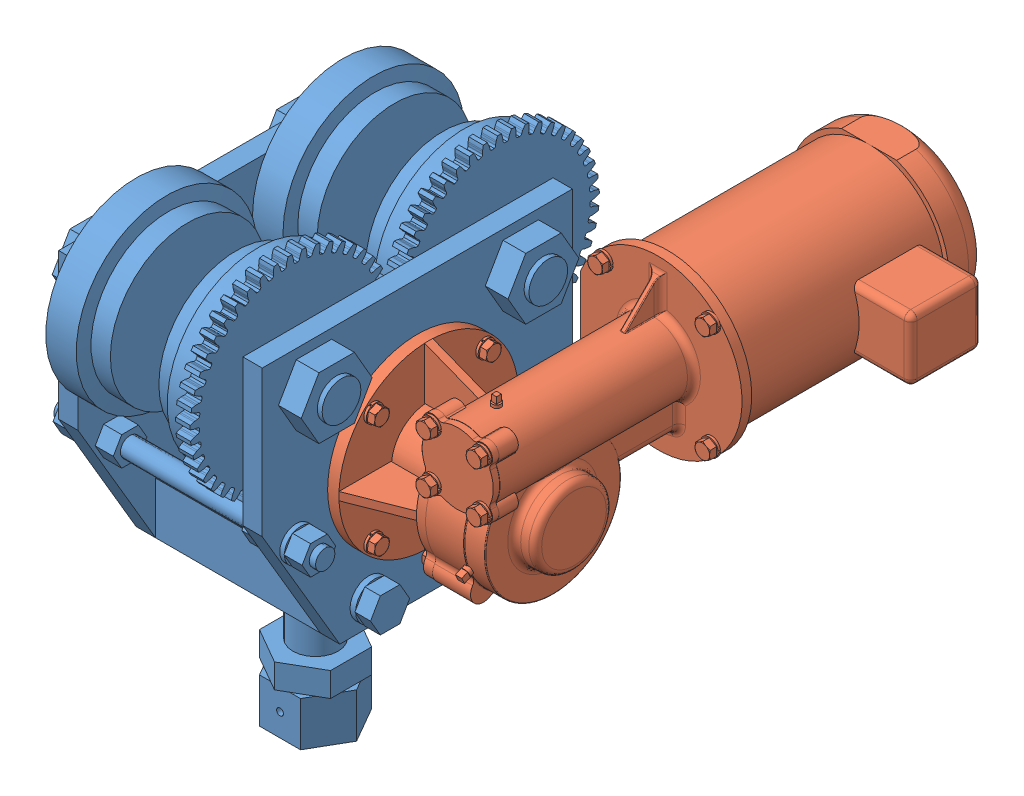
SolidWorks assembly M2630C-RH, configuration Default. Lengths in mm.
Overall size (465.77 492.84 570.37).
2 component instances, 2 part files, 3 mates.
Components (placement in the parent):
- Copy of M2630C-TROLLEY-SECTION^M2630C-RH-1: Copy of M2630C-TROLLEY-SECTION^M2630C-RH [3.25 PAT TRACK] at origin size (257.18 492.84 402.11) (virtual)
- Copy of SDT GEAR REDUCER RH M2630 TEMPLATE^M2630C-RH-1: Copy of SDT GEAR REDUCER RH M2630 TEMPLATE^M2630C-RH [Default] at (212.725 137.4775 0) size (238.76 237.33 457.42) (virtual)
Mates (geometry in assembly coordinates):
- Coincident1: coincident aligned: plane of Copy of M2630C-TROLLEY-SECTION^M2630C-RH-1 through (0 137.4775 0) normal (0 1 0); plane of Copy of SDT GEAR REDUCER RH M2630 TEMPLATE^M2630C-RH-1 through (212.725 137.4775 0) normal (0 1 0)
- Coincident2: coincident aligned: plane of Copy of M2630C-TROLLEY-SECTION^M2630C-RH-1 through (0 0 0) normal (0 0 1); plane of Copy of SDT GEAR REDUCER RH M2630 TEMPLATE^M2630C-RH-1 through (212.725 137.4775 0) normal (0 0 1)
- Distance1: distance = 17.4625 mm aligned: plane of Copy of M2630C-TROLLEY-SECTION^M2630C-RH-1 through (80.9625 0 -152.4) normal (-1 0 0); plane of Copy of SDT GEAR REDUCER RH M2630 TEMPLATE^M2630C-RH-1 through (98.425 137.4775 0) normal (-1 0 0)
